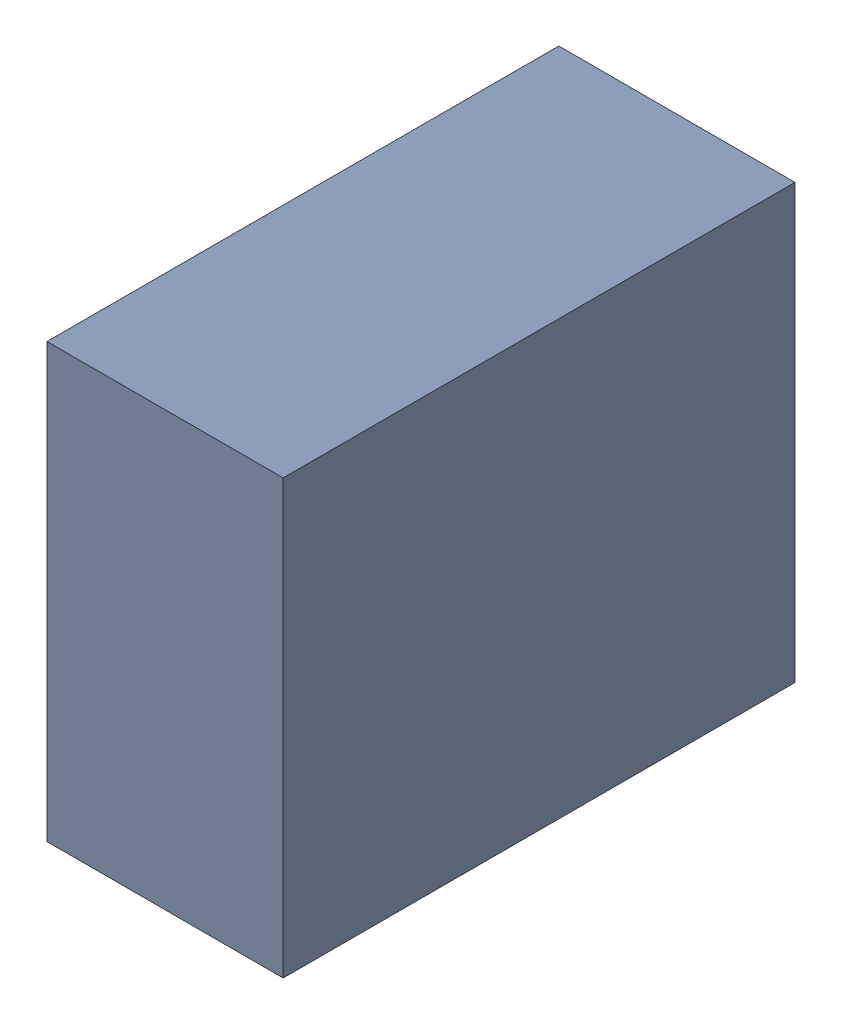
SolidWorks assembly C30_TDA4, configuration Standard. Lengths in mm.
Overall size (0.6 1.1 1.3).
2 component instances, 1 part files, 0 mates.
Components (placement in the parent):
- 885542376-1: 885542376 [Standard] at (-4.24 -58.67 0) size (0.6 1.1 1.3)
  - Extruded_25-1: Extruded_25 [Standard] at origin size (0.6 1.1 1.3)
